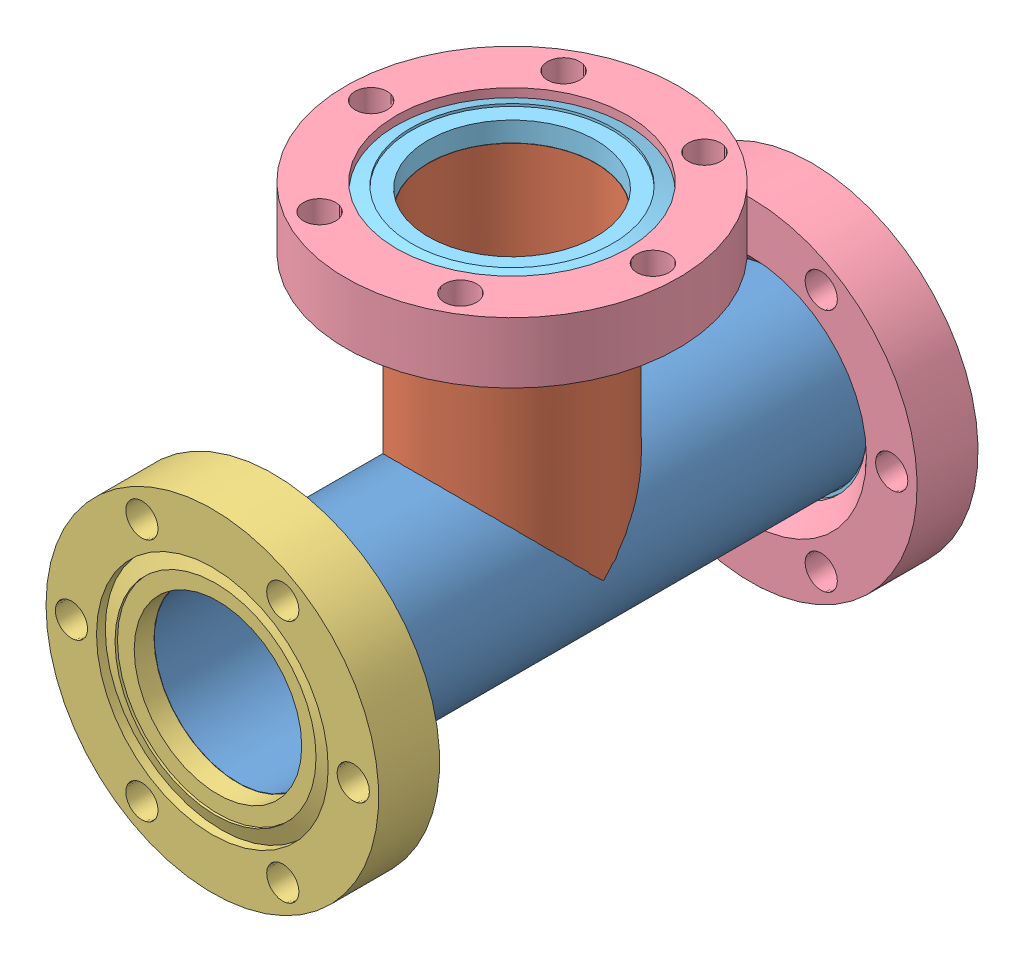
SolidWorks assembly T275-404002_a, configuration Default. Lengths in mm.
Overall size (69.34 97.13 124.92).
9 component instances, 5 part files, 0 mates.
Components (placement in the parent):
- 404002-001-1: 404002-001 [Default] at origin size (38.1 38.1 114.3)
- 404002-002-1: 404002-002 [Default] at (0 0 57.15) x (-1 0 0) z (0 1 0) size (38.1 38.1 58.53)
- 110014 (2.75 X 1.5 NR)_1-1: 110014 (2.75 X 1.5 NR)_1 [Default] at (0 0 113.2586) x (0 0 1) z (-1 0 0) size (12.7 69.34 69.34)
- 100014 (2.75 X 1.5 R)-1: 100014 (2.75 X 1.5 R) [Default] at (0 62.4586 57.15) x (0 -1 0) z (1 0 0) size (12.7 69.34 69.34)
  - 100014 (2.75 X 1.5 REC)_1-1: 100014 (2.75 X 1.5 REC)_1 [Default] at origin size (12.7 69.34 69.34)
  - 100014 (2.75 X 1.5 INS)-1: 100014 (2.75 X 1.5 INS) [Default] at (1.17 0 0) x (1 0 0) z (0 0.994423 -0.105464) size (6.96 48.1 48.1)
- 100014 (2.75 X 1.5 R)-2: 100014 (2.75 X 1.5 R) [Default] at (0 0 -5.3086) x (0 0 1) z (-1 0 0) size (12.7 69.34 69.34)
  - 100014 (2.75 X 1.5 REC)_1-1: 100014 (2.75 X 1.5 REC)_1 [Default] at origin size (12.7 69.34 69.34)
  - 100014 (2.75 X 1.5 INS)-1: 100014 (2.75 X 1.5 INS) [Default] at (1.17 0 0) x (1 0 0) z (0 0.994423 -0.105464) size (6.96 48.1 48.1)
